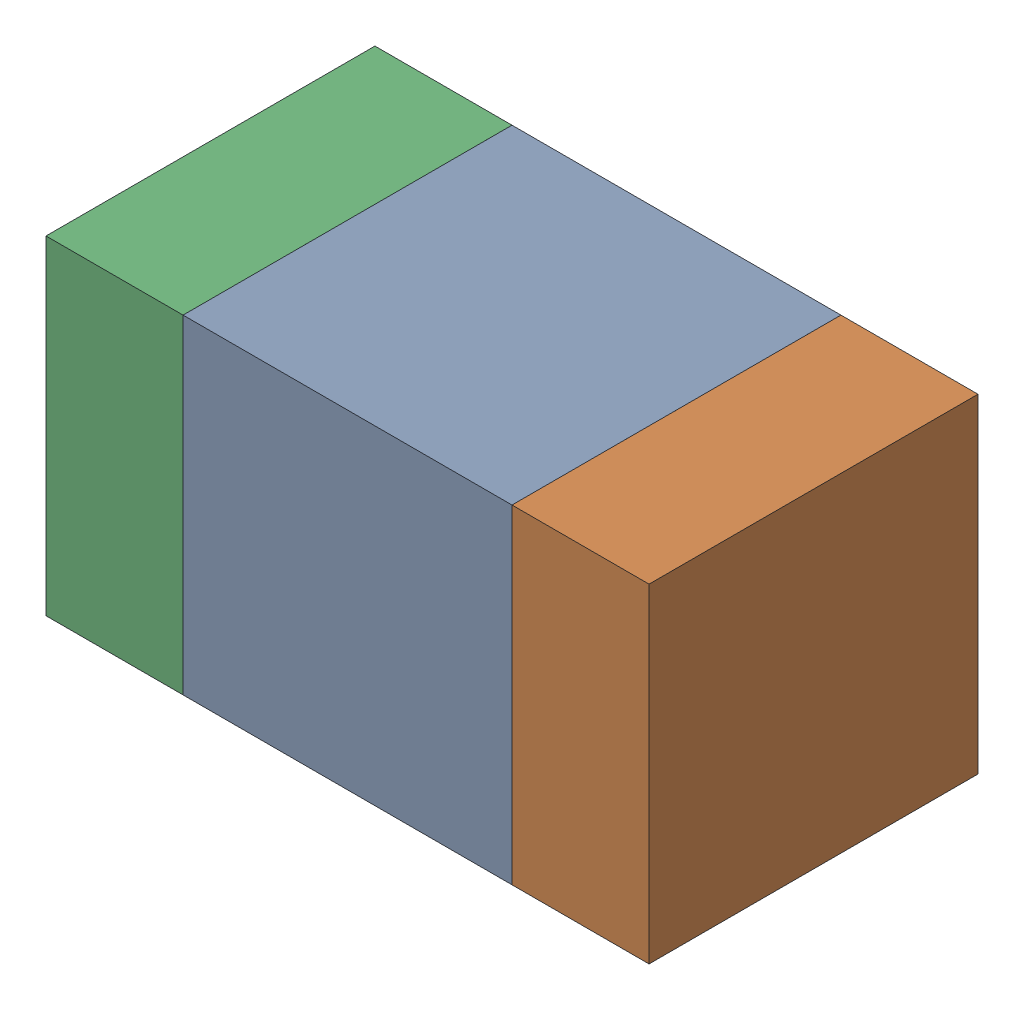
SolidWorks assembly C401PCB, configuration Default. Lengths in mm.
Overall size (1.1 0.6 0.6).
6 component instances, 2 part files, 0 mates.
Components (placement in the parent):
- 761606048-1: 761606048 [Default] at (129.2 105.2 0) size (0.6 0.6 0.6)
  - Extruded_9-1: Extruded_9 [Default] at origin size (0.6 0.6 0.6)
- 854785160-1: 854785160 [Default] at (129.625 105.2 0) size (0.25 0.6 0.6)
  - Extruded_19-1: Extruded_19 [Default] at origin size (0.25 0.6 0.6)
- 854785160-2: 854785160 [Default] at (128.775 105.2 0) size (0.25 0.6 0.6)
  - Extruded_19-1: Extruded_19 [Default] at origin size (0.25 0.6 0.6)
